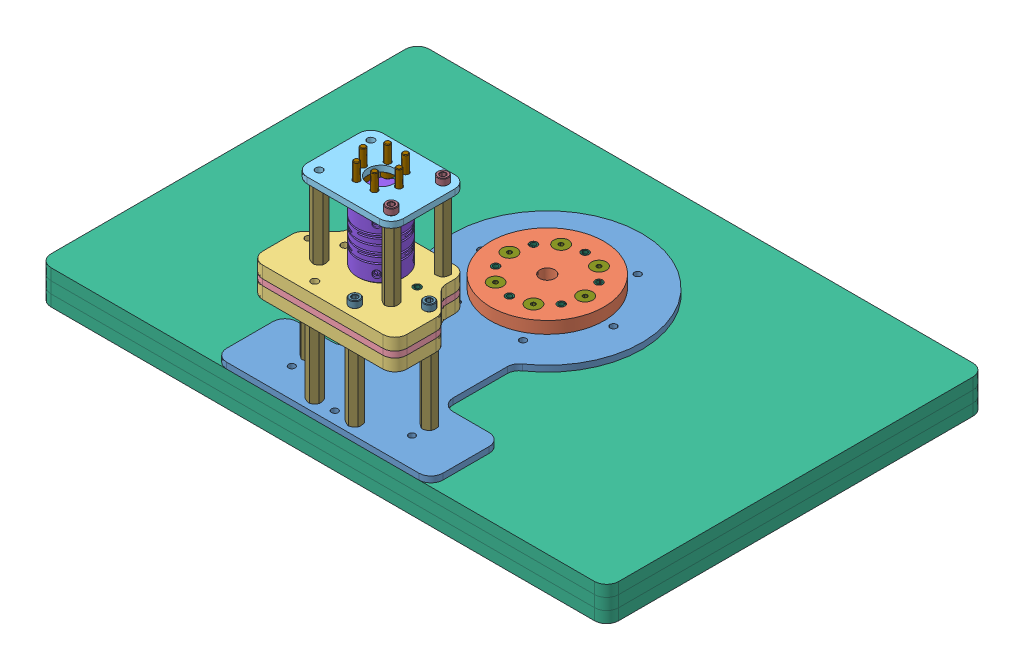
SolidWorks assembly A_1_000, configuration Default. Lengths in mm.
Overall size (300 125.25 200).
69 component instances, 17 part files, 77 mates.
Components (placement in the parent):
- A_1_001-1: A_1_001 [Default] at (-85.4123 81.7054 215.044) size (114.3 3.17 168.65)
- A_1_002-1: A_1_002 [Default] at (64.5877 84.8804 96.393) size (60 6.35 60)
- A_1_003-2: A_1_003 [Default] at (26.4877 122.9804 215.0431) size (76.2 6.35 50.8)
- A_1_003-3: A_1_003 [Default] at (26.4877 132.5054 215.0431) size (76.2 6.35 50.8)
- A_1_004-2: A_1_004 [Default] at (26.4877 129.3304 215.0431) size (76.2 3.17 50.8)
- A_1_005-1: A_1_005 [Default] at (64.5877 176.9554 184.2431) x (1 0 0) z (0 1 0) size (50.8 40 3.17)
- A_1_006-4: A_1_006 [Default] at (-85.4123 75.7054 215.044) size (300 6 200)
- A_1_006-5: A_1_006 [Default] at (-85.4123 69.7054 215.044) size (300 6 200)
- A_1_006-3: A_1_006 [Default] at (-85.4123 63.7054 215.044) size (300 6 200)
- 110302272750_SB6900ZZ-3: 110302272750_SB6900ZZ [Default] at (64.5877 132.5054 184.2431) x (0 1 0) z (0 0 1) size (6 22 22)
- 110302272750_SB6900ZZ-2: 110302272750_SB6900ZZ [Default] at (64.5877 123.3304 184.2431) x (0 1 0) z (0 0 1) size (6 22 22)
- 110300126030_CPL25-6-10-1: 110300126030_CPL25-6-10 [Default] at (64.5877 170.8554 184.2431) x (0 -1 0) z (0.60776 0 0.794121) size (31 25 25)
- 110100141750_CB3-12-1: 110100141750_CB3-12 [Default] at (55.0877 176.9554 184.2431) x (0 1 0) z (0.267593 0 0.963532) size (15 5.5 5.5)
- 110300088140_SFRMHP10-55-F5-P4-1: 110300088140_SFRMHP10-55-F5-P4 [Default] at (64.5877 157.9804 184.2431) x (0.887712 0 -0.4604) z (0 -1 0) size (10 10 60)
- 110300250540_LBNR6-1: 110300250540_LBNR6 [Default] at (64.5877 79.2054 96.393) x (0 -1 0) z (0.5 0 0.866025) size (5 11.5 10)
- 110100141750_CB3-12-2: 110100141750_CB3-12 [Default] at (59.8377 176.9554 176.0158) x (0 1 0) z (-0.700647 0 0.713508) size (15 5.5 5.5) (hidden)
- 110100141750_CB3-12-3: 110100141750_CB3-12 [Default] at (69.3377 176.9554 176.0158) x (0 1 0) z (-0.96824 0 -0.250024) size (15 5.5 5.5) (hidden)
- 110100141750_CB3-12-4: 110100141750_CB3-12 [Default] at (74.0877 176.9554 184.2431) x (0 1 0) z (-0.267593 0 -0.963532) size (15 5.5 5.5) (hidden)
- 110100141750_CB3-12-5: 110100141750_CB3-12 [Default] at (69.3377 176.9554 192.4703) x (0 1 0) z (0.700647 0 -0.713508) size (15 5.5 5.5) (hidden)
- 110100141750_CB3-12-6: 110100141750_CB3-12 [Default] at (59.8377 176.9554 192.4703) x (0 1 0) z (0.96824 0 0.250024) size (15 5.5 5.5) (hidden)
- 91115A135-28: 91115A135 [91115A135] at (45.5377 157.9054 170.5931) x (-0.944772 0 0.327729) z (0 1 0) size (6.35 7.33 39.19)
- 91115A135-23: 91115A135 [91115A135] at (83.6377 157.9054 170.5931) x (-0.960942 0 -0.27675) z (0 1 0) size (6.35 7.33 39.19)
- 91115A135-27: 91115A135 [91115A135] at (45.5377 157.9054 197.8931) x (-0.991247 0 0.132023) z (0 1 0) size (6.35 7.33 39.19)
- 91115A135-22: 91115A135 [91115A135] at (83.6377 157.9054 197.8931) x (-0.999891 0 0.014762) z (0 1 0) size (6.35 7.33 39.19)
- 91115A135-24: 91115A135 [91115A135] at (32.8377 103.9304 190.593) x (0.992439 0 0.122738) z (0 -1 0) size (6.35 7.33 39.19)
- 91115A135-29: 91115A135 [91115A135] at (96.3377 103.9304 190.593) x (-0.565203 0 0.824952) z (0 -1 0) size (6.35 7.33 39.19)
- 91115A135-25: 91115A135 [91115A135] at (54.0044 103.9304 208.6931) x (0.977731 0 -0.20986) z (0 1 0) size (6.35 7.33 39.19)
- 91115A135-26: 91115A135 [91115A135] at (75.171 103.9304 208.6931) x (0.998294 0 -0.058385) z (0 1 0) size (6.35 7.33 39.19)
- 92196A146-5: 92196A146 [92196A146] at (83.6377 170.6054 170.5931) x (1 0 0) z (0 -1 0) size (5.74 5.74 13.47)
- 92196A146-2: 92196A146 [92196A146] at (83.6377 170.6054 197.8931) x (1 0 0) z (0 -1 0) size (5.74 5.74 13.47)
- 92196A146-6: 92196A146 [92196A146] at (96.3377 91.2304 190.593) x (-0.837169 0 -0.546944) z (0 1 0) size (5.74 5.74 13.47)
- 92196A146-4: 92196A146 [92196A146] at (75.171 91.2304 208.6931) x (-0.837169 0 -0.546944) z (0 1 0) size (5.74 5.74 13.47)
- 92196A152-5: 92196A152 [92196A152] at (96.3377 116.6304 190.593) x (-0.837169 0 -0.546944) z (0 -1 0) size (5.74 5.74 26.24)
- 92196A152-2: 92196A152 [92196A152] at (75.171 116.6304 208.6931) x (-0.837169 0 -0.546944) z (0 -1 0) size (5.74 5.74 26.24)
- 92196A152-6: 92196A152 [92196A152] at (83.6377 145.2054 197.8931) x (1 0 0) z (0 1 0) size (5.74 5.74 26.24)
- 92196A152-4: 92196A152 [92196A152] at (83.6377 145.2054 170.5931) x (1 0 0) z (0 1 0) size (5.74 5.74 26.24)
- 92373A213-1: 92373A213 [92373A213] at (83.6377 130.9179 184.2431) x (1 0 0) z (0 1 0) size (4.08 4.11 15.88)
- 92373A213-3: 92373A213 [92373A213] at (64.5877 83.2929 76.393) x (1 0 0) z (0 -1 0) size (4.08 4.11 15.88)
- 92210A151-1: 92210A151 [92210A151] at (74.5877 91.2304 79.0725) x (1 0 0) z (0 1 0) size (7.8 7.8 19.48)
- 95170A355-1: 95170A355 [95170A355] at (74.5877 81.7054 79.0725) x (-0.774226 0 -0.63291) z (-0.63291 0 0.774226) size (8.33 3.94 9.17)
- 92196A146-7: 92196A146 [92196A146] at (45.5377 170.6054 197.8931) x (-1 0 0) z (0 -1 0) size (5.74 5.74 13.47) (hidden)
- 92196A146-8: 92196A146 [92196A146] at (45.5377 170.6054 170.5931) x (-1 0 0) z (0 -1 0) size (5.74 5.74 13.47) (hidden)
- 92373A213-9: 92373A213 [92373A213] at (45.5377 130.9179 184.2431) x (-1 0 0) z (0 -1 0) size (4.08 4.11 15.88) (hidden)
- 92196A152-7: 92196A152 [92196A152] at (32.8377 116.6304 190.593) x (0.837169 0 -0.546944) z (0 -1 0) size (5.74 5.74 26.24) (hidden)
- 92196A152-8: 92196A152 [92196A152] at (54.0044 116.6304 208.6931) x (0.837169 0 -0.546944) z (0 -1 0) size (5.74 5.74 26.24) (hidden)
- 92196A152-9: 92196A152 [92196A152] at (45.5377 145.2054 197.8931) x (-1 0 0) z (0 1 0) size (5.74 5.74 26.24) (hidden)
- 92196A152-10: 92196A152 [92196A152] at (45.5377 145.2054 170.5931) x (-1 0 0) z (0 1 0) size (5.74 5.74 26.24) (hidden)
- 92196A146-9: 92196A146 [92196A146] at (54.0044 91.2304 208.6931) x (0.837169 0 -0.546944) z (0 1 0) size (5.74 5.74 13.47) (hidden)
- 92196A146-10: 92196A146 [92196A146] at (32.8377 91.2304 190.593) x (0.837169 0 -0.546944) z (0 1 0) size (5.74 5.74 13.47) (hidden)
- 92373A213-4: 92373A213 [92373A213] at (81.9082 83.2929 86.393) x (0.5 0 0.866025) z (0 -1 0) size (4.08 4.11 15.88)
- 92373A213-5: 92373A213 [92373A213] at (81.9082 83.2929 106.393) x (-0.5 0 0.866025) z (0 -1 0) size (4.08 4.11 15.88)
- 92373A213-6: 92373A213 [92373A213] at (64.5877 83.2929 116.393) x (-1 0 0) z (0 -1 0) size (4.08 4.11 15.88)
- 92373A213-7: 92373A213 [92373A213] at (47.2672 83.2929 106.393) x (-0.5 0 -0.866025) z (0 -1 0) size (4.08 4.11 15.88)
- 92373A213-8: 92373A213 [92373A213] at (47.2672 83.2929 86.393) x (0.5 0 -0.866025) z (0 -1 0) size (4.08 4.11 15.88)
- 95170A355-2: 95170A355 [95170A355] at (84.5877 81.7054 96.393) x (0.161003 0 -0.986954) z (-0.986954 0 -0.161003) size (8.33 3.94 9.17)
- 95170A355-3: 95170A355 [95170A355] at (74.5877 81.7054 113.7135) x (0.935229 0 -0.354044) z (-0.354044 0 -0.935229) size (8.33 3.94 9.17)
- 95170A355-4: 95170A355 [95170A355] at (54.5877 81.7054 113.7135) x (0.774226 0 0.63291) z (0.63291 0 -0.774226) size (8.33 3.94 9.17)
- 95170A355-5: 95170A355 [95170A355] at (44.5877 81.7054 96.393) x (-0.161003 0 0.986954) z (0.986954 0 0.161003) size (8.33 3.94 9.17)
- 95170A355-6: 95170A355 [95170A355] at (54.5877 81.7054 79.0725) x (-0.935229 0 0.354044) z (0.354044 0 0.935229) size (8.33 3.94 9.17)
- 92210A151-2: 92210A151 [92210A151] at (84.5877 91.2304 96.393) x (0.5 0 0.866025) z (0 1 0) size (7.8 7.8 19.48)
- 92210A151-3: 92210A151 [92210A151] at (74.5877 91.2304 113.7135) x (-0.5 0 0.866025) z (0 1 0) size (7.8 7.8 19.48)
- 92210A151-4: 92210A151 [92210A151] at (54.5877 91.2304 113.7135) x (-1 0 0) z (0 1 0) size (7.8 7.8 19.48)
- 92210A151-5: 92210A151 [92210A151] at (44.5877 91.2304 96.393) x (-0.5 0 -0.866025) z (0 1 0) size (7.8 7.8 19.48)
- 92210A151-6: 92210A151 [92210A151] at (54.5877 91.2304 79.0725) x (0.5 0 -0.866025) z (0 1 0) size (7.8 7.8 19.48)
- 110100141750_CB3-12-7: 110100141750_CB3-12 [Default] at (59.8377 176.9554 176.0158) x (0 1 0) z (-0.700647 0 0.713508) size (15 5.5 5.5)
- 110100141750_CB3-12-8: 110100141750_CB3-12 [Default] at (69.3377 176.9554 176.0158) x (0 1 0) z (-0.96824 0 -0.250024) size (15 5.5 5.5)
- 110100141750_CB3-12-9: 110100141750_CB3-12 [Default] at (74.0877 176.9554 184.2431) x (0 1 0) z (-0.267593 0 -0.963532) size (15 5.5 5.5)
- 110100141750_CB3-12-10: 110100141750_CB3-12 [Default] at (69.3377 176.9554 192.4703) x (0 1 0) z (0.700647 0 -0.713508) size (15 5.5 5.5)
- 110100141750_CB3-12-11: 110100141750_CB3-12 [Default] at (59.8377 176.9554 192.4703) x (0 1 0) z (0.96824 0 0.250024) size (15 5.5 5.5)
Mates (geometry in assembly coordinates):
- Coincident6: coincident anti-aligned: plane of A_1_003-2 through (26.4877 129.3304 164.2431) normal (0 1 0); plane of A_1_004-2 through (26.4877 129.3304 164.2431) normal (0 -1 0)
- Coincident7: coincident anti-aligned: plane of A_1_004-2 through (26.4877 132.5054 164.2431) normal (0 1 0); plane of A_1_003-3 through (26.4877 132.5054 164.2431) normal (0 -1 0)
- Concentric17: concentric anti-aligned: cylinder of A_1_003-3 through (64.5877 138.8554 184.2431) axis (0 -1 0) radius 11; cylinder of 110302272750_SB6900ZZ-3 through (64.5877 132.5041 184.2431) axis (0 1 0) radius 5
- Coincident13: coincident anti-aligned: plane of A_1_004-2 through (26.4877 132.5054 164.2431) normal (0 1 0); plane of 110302272750_SB6900ZZ-3 through (53.8877 132.5054 184.2431) normal (0 -1 0)
- Concentric18: concentric anti-aligned: cylinder of A_1_003-2 through (64.5877 129.3304 184.2431) axis (0 -1 0) radius 11; cylinder of 110302272750_SB6900ZZ-2 through (64.5877 123.3291 184.2431) axis (0 1 0) radius 5
- Coincident14: coincident anti-aligned: plane of A_1_004-2 through (26.4877 129.3304 164.2431) normal (0 -1 0); plane of 110302272750_SB6900ZZ-2 through (54.7877 129.3304 184.2431) normal (0 1 0)
- Concentric19: concentric anti-aligned: cylinder of A_1_001-1 through (64.5877 81.7054 96.393) axis (0 1 0) radius 4; cylinder of A_1_002-1 through (64.5877 91.2304 96.393) axis (0 -1 0) radius 4
- Concentric20: concentric anti-aligned: cylinder of A_1_001-1 through (64.5877 81.7054 116.393) axis (0 1 0) radius 1.9939; cylinder of A_1_002-1 through (64.5877 91.2304 116.393) axis (0 -1 0) radius 1.9939
- Coincident15: coincident anti-aligned: plane of A_1_001-1 through (-85.4123 84.8804 15.044) normal (0 1 0); plane of A_1_002-1 through (64.5877 84.8804 96.393) normal (0 -1 0)
- Concentric21: concentric anti-aligned: cylinder of 110302272750_SB6900ZZ-3 through (64.5877 132.5041 184.2431) axis (0 1 0) radius 5; cylinder of 110300126030_CPL25-6-10-1 through (64.5877 144.1054 184.2431) axis (0 -1 0) radius 5
- Distance1: distance = 1 mm anti-aligned: plane of 110300126030_CPL25-6-10-1 through (71.437 139.8554 179.0011) normal (0 -1 0); plane of A_1_003-3 through (26.4877 138.8554 164.2431) normal (0 1 0)
- Concentric22: concentric aligned: cylinder of A_1_005-1 through (55.0877 176.9554 184.2431) axis (0 1 0) radius 1.75; cylinder of 110100141750_CB3-12-1 through (55.0877 182.8022 184.2431) axis (0 1 0) radius 1.5
- Coincident17: coincident anti-aligned: plane of A_1_005-1 through (39.1877 176.9554 204.2431) normal (0 -1 0); plane of 110100141750_CB3-12-1 through (53.0402 176.9554 184.8117) normal (0 1 0)
- Concentric32: concentric aligned: cylinder of 110302272750_SB6900ZZ-2 through (64.5877 123.3291 184.2431) axis (0 1 0) radius 5; cylinder of 110300088140_SFRMHP10-55-F5-P4-1 through (64.5877 97.9804 184.2431) axis (0 1 0) radius 5
- Distance2: distance = 25 mm aligned: plane of 110300088140_SFRMHP10-55-F5-P4-1 through (64.5877 97.9804 184.2431) normal (0 -1 0); plane of A_1_003-2 through (26.4877 122.9804 164.2431) normal (0 -1 0)
- Concentric35: concentric aligned: cylinder of A_1_004-2 through (83.6377 132.5054 170.5931) axis (0 -1 0) radius 1.8986; cylinder of A_1_003-3 through (83.6377 138.8554 170.5931) axis (0 -1 0) radius 1.8986
- Concentric36: concentric aligned: cylinder of A_1_003-2 through (83.6377 129.3304 170.5931) axis (0 -1 0) radius 1.8986; cylinder of A_1_004-2 through (83.6377 132.5054 170.5931) axis (0 -1 0) radius 1.8986
- Concentric39: concentric aligned: cylinder of A_1_004-2 through (83.6377 132.5054 197.8931) axis (0 -1 0) radius 1.8986; cylinder of A_1_003-3 through (83.6377 138.8554 197.8931) axis (0 -1 0) radius 1.8986
- Concentric40: concentric aligned: cylinder of A_1_003-2 through (83.6377 129.3304 197.8931) axis (0 -1 0) radius 1.8986; cylinder of A_1_004-2 through (83.6377 132.5054 197.8931) axis (0 -1 0) radius 1.8986
- Concentric54: concentric aligned: cylinder of A_1_001-1 through (32.8377 81.7054 190.593) axis (0 1 0) radius 1.8986; cylinder of A_1_006-4 through (32.8377 75.7054 190.593) axis (0 1 0) radius 3.25
- Concentric55: concentric aligned: cylinder of A_1_001-1 through (96.3377 81.7054 190.593) axis (0 1 0) radius 1.8986; cylinder of A_1_006-4 through (96.3377 75.7054 190.593) axis (0 1 0) radius 3.25
- Coincident30: coincident anti-aligned: plane of A_1_001-1 through (-85.4123 81.7054 15.044) normal (0 -1 0); plane of A_1_006-4 through (-85.4123 81.7054 15.044) normal (0 1 0)
- Concentric56: concentric aligned: cylinder of A_1_006-4 through (32.8377 75.7054 190.593) axis (0 1 0) radius 3.25; cylinder of A_1_006-5 through (32.8377 69.7054 190.593) axis (0 1 0) radius 3.25
- Concentric57: concentric aligned: cylinder of A_1_006-4 through (96.3377 75.7054 190.593) axis (0 1 0) radius 3.25; cylinder of A_1_006-5 through (96.3377 69.7054 190.593) axis (0 1 0) radius 3.25
- Coincident31: coincident anti-aligned: plane of A_1_006-4 through (-85.4123 75.7054 15.044) normal (0 -1 0); plane of A_1_006-5 through (-85.4123 75.7054 15.044) normal (0 1 0)
- Coincident32: coincident anti-aligned: plane of A_1_005-1 through (39.1877 176.9554 204.2431) normal (0 -1 0); plane of 91115A135-28 through (46.7392 176.9554 174.0568) normal (0 1 0)
- Concentric59: concentric aligned: cylinder of A_1_003-3 through (45.5377 138.8554 170.5931) axis (0 -1 0) radius 1.8986; circle of 91115A135-28
- Coincident33: coincident anti-aligned: plane of A_1_003-3 through (26.4877 138.8554 164.2431) normal (0 1 0); plane of 91115A135-28 through (46.7392 138.8554 174.0568) normal (0 -1 0)
- Concentric61: concentric aligned: cylinder of A_1_003-3 through (83.6377 138.8554 170.5931) axis (0 -1 0) radius 1.8986; circle of 91115A135-23
- Coincident34: coincident anti-aligned: plane of A_1_005-1 through (39.1877 176.9554 204.2431) normal (0 -1 0); plane of 91115A135-23 through (82.6231 176.9554 174.116) normal (0 1 0)
- Coincident35: coincident anti-aligned: plane of A_1_005-1 through (39.1877 176.9554 204.2431) normal (0 -1 0); plane of 91115A135-27 through (46.0217 176.9554 201.5271) normal (0 1 0)
- Coincident36: coincident anti-aligned: plane of A_1_005-1 through (39.1877 176.9554 204.2431) normal (0 -1 0); plane of 91115A135-22 through (83.6918 176.9554 201.5588) normal (0 1 0)
- Concentric68: concentric anti-aligned: cylinder of A_1_003-2 through (32.8377 129.3304 190.593) axis (0 -1 0) radius 1.8986; circle of 91115A135-24
- Concentric69: concentric aligned: cylinder of A_1_001-1 through (32.8377 81.7054 190.593) axis (0 1 0) radius 1.8986; circle of 91115A135-24
- Coincident39: coincident anti-aligned: plane of A_1_003-2 through (26.4877 122.9804 164.2431) normal (0 -1 0); plane of 91115A135-24 through (32.3877 122.9804 194.2315) normal (0 1 0)
- Coincident40: coincident anti-aligned: plane of A_1_001-1 through (-85.4123 84.8804 15.044) normal (0 1 0); plane of 91115A135-24 through (32.3877 84.8804 194.2315) normal (0 -1 0)
- Concentric70: concentric anti-aligned: cylinder of A_1_003-2 through (96.3377 129.3304 190.593) axis (0 -1 0) radius 1.8986; circle of 91115A135-29
- Concentric71: concentric aligned: cylinder of A_1_001-1 through (96.3377 81.7054 190.593) axis (0 1 0) radius 1.8986; circle of 91115A135-29
- Coincident41: coincident anti-aligned: plane of A_1_003-2 through (26.4877 122.9804 164.2431) normal (0 -1 0); plane of 91115A135-29 through (93.3133 122.9804 188.5209) normal (0 1 0)
- Concentric72: concentric aligned: cylinder of A_1_003-2 through (54.0044 129.3304 208.6931) axis (0 -1 0) radius 1.8986; circle of 91115A135-25
- Coincident42: coincident anti-aligned: plane of A_1_003-2 through (26.4877 122.9804 164.2431) normal (0 -1 0); plane of 91115A135-25 through (53.235 122.9804 205.1085) normal (0 1 0)
- Concentric73: concentric aligned: cylinder of A_1_003-2 through (75.171 129.3304 208.6931) axis (0 -1 0) radius 1.8986; circle of 91115A135-26
- Coincident43: coincident anti-aligned: plane of A_1_003-2 through (26.4877 122.9804 164.2431) normal (0 -1 0); plane of 91115A135-26 through (74.957 122.9804 205.0331) normal (0 1 0)
- Concentric85: concentric anti-aligned: cylinder of A_1_005-1 through (45.5377 176.9554 170.5931) axis (0 1 0) radius 1.8986; circle of 91115A135-28
- Concentric86: concentric anti-aligned: cylinder of A_1_005-1 through (83.6377 176.9554 170.5931) axis (0 1 0) radius 1.8986; circle of 91115A135-23
- Concentric89: concentric anti-aligned: cylinder of A_1_005-1 through (83.6377 176.9554 197.8931) axis (0 1 0) radius 1.8986; circle of 91115A135-22
- Concentric90: concentric anti-aligned: cylinder of A_1_005-1 through (45.5377 176.9554 197.8931) axis (0 1 0) radius 1.8986; circle of 91115A135-27
- Concentric91: concentric aligned: cylinder of A_1_006-5 through (96.3377 69.7054 190.593) axis (0 1 0) radius 3.25; cylinder of A_1_006-3 through (96.3377 63.7054 190.593) axis (0 1 0) radius 3.25
- Concentric92: concentric aligned: cylinder of A_1_006-5 through (32.8377 69.7054 190.593) axis (0 1 0) radius 3.25; cylinder of A_1_006-3 through (32.8377 63.7054 190.593) axis (0 1 0) radius 3.25
- Coincident52: coincident anti-aligned: plane of A_1_006-5 through (-85.4123 69.7054 15.044) normal (0 -1 0); plane of A_1_006-3 through (-85.4123 69.7054 15.044) normal (0 1 0)
- Concentric109: concentric anti-aligned: cylinder of A_1_001-1 through (64.5877 81.7054 96.393) axis (0 1 0) radius 4; circle of 110300250540_LBNR6-1
- Parallel1: parallel anti-aligned: plane of A_1_006-4 through (59.7877 75.7054 93.6217) normal (0.5 0 0.866025); plane of 110300250540_LBNR6-1 through (64.5467 76.7054 90.6432) normal (-0.5 0 -0.866025)
- Coincident71: coincident anti-aligned: plane of A_1_001-1 through (-85.4123 81.7054 15.044) normal (0 -1 0); plane of 110300250540_LBNR6-1 through (64.5877 81.7054 96.393) normal (0 1 0)
- Concentric110: concentric anti-aligned: cylinder of A_1_005-1 through (83.6377 176.9554 170.5931) axis (0 1 0) radius 1.8986; circle of 92196A146-5
- Coincident72: coincident anti-aligned: plane of A_1_005-1 through (39.1877 180.1304 204.2431) normal (0 1 0); plane of 92196A146-5 through (83.6377 180.1304 170.5931) normal (0 -1 0)
- Concentric111: concentric anti-aligned: cylinder of A_1_005-1 through (83.6377 176.9554 197.8931) axis (0 1 0) radius 1.8986; circle of 92196A146-2
- Coincident73: coincident anti-aligned: plane of A_1_005-1 through (39.1877 180.1304 204.2431) normal (0 1 0); plane of 92196A146-2 through (83.6377 180.1304 197.8931) normal (0 -1 0)
- Concentric112: concentric aligned: cylinder of A_1_001-1 through (96.3377 81.7054 190.593) axis (0 1 0) radius 1.8986; circle of 92196A146-6
- Coincident74: coincident anti-aligned: plane of A_1_001-1 through (-85.4123 81.7054 15.044) normal (0 -1 0); plane of 92196A146-6 through (96.3377 81.7054 190.593) normal (0 1 0)
- Concentric113: concentric aligned: cylinder of A_1_001-1 through (75.171 81.7054 208.6931) axis (0 1 0) radius 1.8986; circle of 92196A146-4
- Coincident75: coincident anti-aligned: plane of A_1_001-1 through (-85.4123 81.7054 15.044) normal (0 -1 0); plane of 92196A146-4 through (75.171 81.7054 208.6931) normal (0 1 0)
- Concentric114: concentric aligned: cylinder of A_1_003-3 through (96.3377 138.8554 190.593) axis (0 -1 0) radius 1.8986; circle of 92196A152-5
- Coincident76: coincident anti-aligned: plane of A_1_003-3 through (26.4877 138.8554 164.2431) normal (0 1 0); plane of 92196A152-5 through (96.3377 138.8554 190.593) normal (0 -1 0)
- Concentric115: concentric aligned: cylinder of A_1_003-3 through (75.171 138.8554 208.6931) axis (0 -1 0) radius 1.8986; circle of 92196A152-2
- Coincident77: coincident anti-aligned: plane of A_1_003-3 through (26.4877 138.8554 164.2431) normal (0 1 0); plane of 92196A152-2 through (75.171 138.8554 208.6931) normal (0 -1 0)
- Concentric116: concentric anti-aligned: cylinder of A_1_003-2 through (83.6377 129.3304 197.8931) axis (0 -1 0) radius 1.8986; circle of 92196A152-6
- Coincident78: coincident anti-aligned: plane of A_1_003-2 through (26.4877 122.9804 164.2431) normal (0 -1 0); plane of 92196A152-6 through (83.6377 122.9804 197.8931) normal (0 1 0)
- Concentric117: concentric anti-aligned: cylinder of A_1_003-2 through (83.6377 129.3304 170.5931) axis (0 -1 0) radius 1.8986; circle of 92196A152-4
- Coincident79: coincident anti-aligned: plane of A_1_003-2 through (26.4877 122.9804 164.2431) normal (0 -1 0); plane of 92196A152-4 through (83.6377 122.9804 170.5931) normal (0 1 0)
- Concentric118: concentric anti-aligned: cylinder of A_1_003-3 through (83.6377 132.5054 184.2431) axis (0 1 0) radius 1.9939; circle of 92373A213-1
- Coincident80: coincident aligned: plane of A_1_003-3 through (26.4877 138.8554 164.2431) normal (0 1 0); plane of 92373A213-1 through (83.6377 138.8554 184.2431) normal (0 1 0)
- Concentric119: concentric anti-aligned: cylinder of A_1_002-1 through (64.5877 91.2304 76.393) axis (0 -1 0) radius 1.9939; circle of 92373A213-3
- Coincident81: coincident aligned: plane of A_1_002-1 through (64.5877 91.2304 96.393) normal (0 1 0); plane of 92373A213-3 through (64.5877 91.2304 76.393) normal (0 1 0)
- Concentric120: concentric aligned: cylinder of A_1_002-1 through (74.5877 91.2304 79.0725) axis (0 -1 0) radius 1.8986; circle of 92210A151-1
- Coincident82: coincident aligned: plane of A_1_002-1 through (64.5877 91.2304 96.393) normal (0 1 0); plane of 92210A151-1 through (74.5877 91.2304 80.8251) normal (0 1 0)
- Concentric121: concentric anti-aligned: cylinder of A_1_001-1 through (74.5877 81.7054 79.0725) axis (0 1 0) radius 1.8986; circle of 95170A355-1
- Coincident83: coincident anti-aligned: plane of A_1_001-1 through (-85.4123 81.7054 15.044) normal (0 -1 0); plane of 95170A355-1 through (77.4881 81.7054 75.5244) normal (0 1 0)
